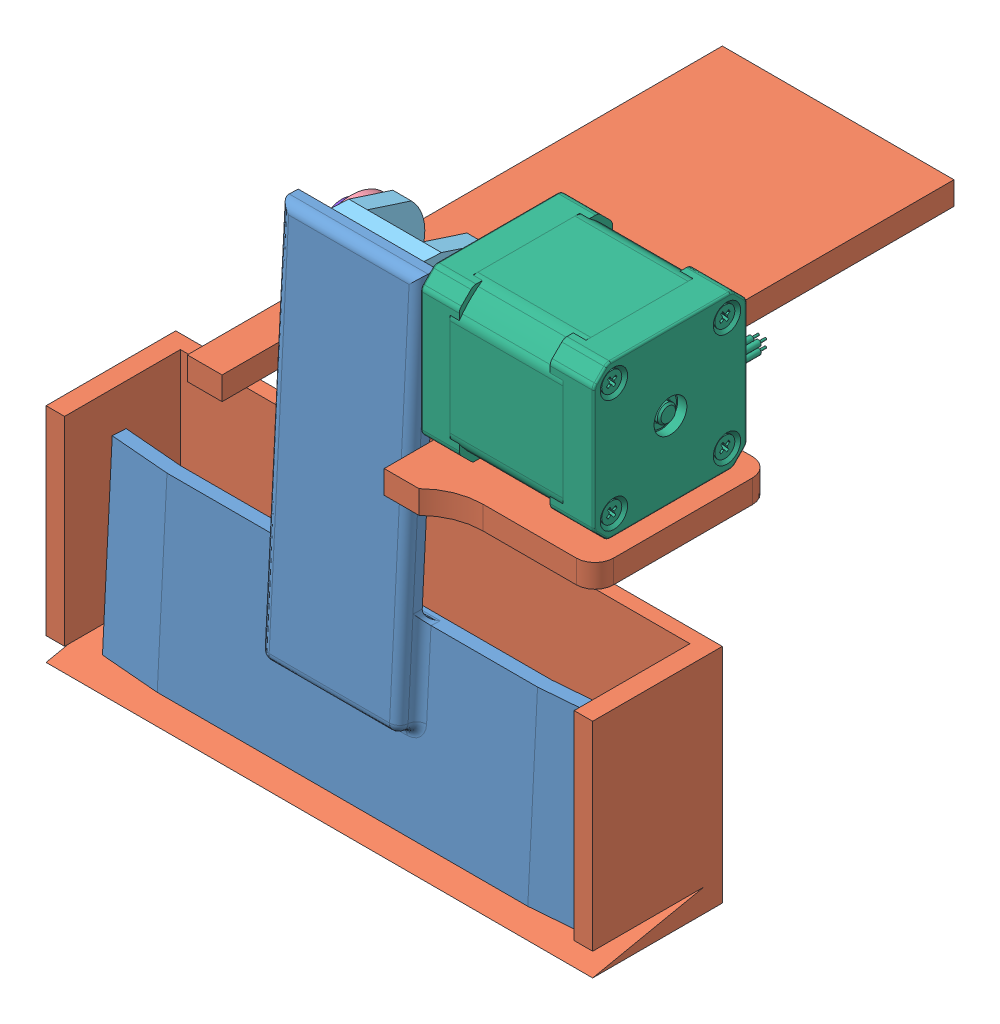
SolidWorks assembly ScoopClawAssembly_m2, configuration Default. Lengths in mm.
Overall size (149.86 138.94 146.69).
8 component instances, 8 part files, 19 mates.
Components (placement in the parent):
- Scooper_m2-1: Scooper_m2 [Default] at (144.6073 -34.5841 76.4289) x (1 0 0) z (0 0.052593 0.998616) size (134.49 132.08 10.33)
- Scooper_Base_m2-1: Scooper_Base_m2 [Default] at (144.6073 -61.534 72.0438) size (149.86 96.84 146.69)
- HC-SR04-UltrasonicSensor v7-2: HC-SR04-UltrasonicSensor v7 [Default] at (144.5683 -48.834 47.0588) x (-1 0 0) z (0 0 1) size (45.45 26.2 17.79)
- Hinge_Part1_base_side-1: Hinge_Part1_base_side [Default] at (144.6073 35.3035 61.4739) size (35.56 29.45 25.4)
- Hinge_Part2__scoop_sdie-1: Hinge_Part2__scoop_sdie [Default] at (144.6073 56.9297 75.4245) x (1 0 0) z (0 0.998616 -0.052593) size (25.4 24.06 25.4)
- 17HM19-2004S-1: 17HM19-2004S [По умолчанию] at (214.4273 69.2601 59.7763) x (0 -0.999984 0.005702) z (0 -0.005702 -0.999984) size (42.19 71.6 51.3)
- Hinge_NEMA17_m2-1: Hinge_NEMA17_m2 [Default] at (162.3873 69.2573 59.755) x (0 -0.999973 0.007334) z (-1 0 0) size (12.7 12.7 38.1)
- Hinge_Cap_m2-1: Hinge_Cap_m2 [Default] at (126.8273 56.195 61.4739) x (0 1 0) z (0 0 1) size (12.7 2.54 12.7)
Mates (geometry in assembly coordinates):
- Concentric1: concentric: cylinder of Scooper_Base_m2-1 through (157.6883 -48.834 58.7088) axis (0 0 -1) radius 8.2697; cylinder of HC-SR04-UltrasonicSensor v7-2 through (157.6883 -48.834 48.6588) axis (0 0 1) radius 8
- Coincident1: coincident: plane of Scooper_Base_m2-1 through (144.6073 -61.534 52.3588) normal (0 0 -1); plane of HC-SR04-UltrasonicSensor v7-2 through (144.5683 -56.2197 52.3588) normal (0 0 1)
- Coincident2: coincident: plane of Scooper_Base_m2-1 through (144.6073 35.3035 72.0438) normal (0 1 0); plane of Hinge_Part1_base_side-1 through (144.6073 35.3035 61.4739) normal (0 -1 0)
- Coincident4: coincident: plane of Scooper_Base_m2-1 through (166.8323 -61.535 74.1739) normal (0 0 1); plane of Hinge_Part1_base_side-1 through (126.8273 48.321 74.1739) normal (0 0 1)
- Distance1: distance = 4.445 mm: plane of Hinge_Part1_base_side-1 through (162.3873 48.321 74.1739) normal (1 0 0); plane of Scooper_Base_m2-1 through (166.8323 -61.535 113.2075) normal (-1 0 0)
- Coincident7: coincident: plane of Hinge_Part1_base_side-1 through (157.3073 52.0471 61.4739) normal (-1 0 0); plane of Hinge_Part2__scoop_sdie-1 through (157.3073 69.2113 67.1471) normal (1 0 0)
- Coincident8: coincident: plane of Scooper_m2-1 through (144.6073 -34.3838 80.2336) normal (0 -0.052593 -0.998616); plane of Hinge_Part2__scoop_sdie-1 through (144.6073 56.9297 75.4245) normal (0 0.052593 0.998616)
- Distance2: distance = 6.35 mm: plane of Scooper_m2-1 through (163.6573 -34.1166 85.3066) normal (1 0 0); plane of Hinge_Part2__scoop_sdie-1 through (157.3073 69.2113 67.1471) normal (1 0 0)
- LimitDistance1: limit distance = 17.4872 mm: point of Scooper_m2-1; plane of Scooper_Base_m2-1 through (144.6073 -61.534 56.1688) normal (0 0 1)
- Distance4: distance = 76.2 mm: line of Scooper_m2-1 through (163.6573 -6.4824 78.7642) axis (-1 0 0); line of Hinge_Part2__scoop_sdie-1 through (131.9073 69.6121 74.7566) axis (1 0 0)
- LimitDistance2: limit distance = 36.8451 mm: plane of Scooper_Base_m2-1 through (144.6073 35.3035 72.0438) normal (0 1 0); line of Scooper_m2-1 through (163.6573 72.1486 74.623) axis (-1 0 0)
- Parallel1: parallel: plane of Scooper_Base_m2-1 through (144.6073 35.3035 72.0438) normal (0 1 0); plane of 17HM19-2004S-1 through (174.9273 35.195 46.8328) normal (0 -1 0)
- Concentric6: concentric: circle of 17HM19-2004S-1; circle of Hinge_NEMA17_m2-1
- Coincident19: coincident: plane of 17HM19-2004S-1 through (164.9273 56.195 61.4739) normal (-1 0 0); plane of Hinge_NEMA17_m2-1 through (164.9273 56.195 61.4739) normal (1 0 0)
- Concentric7: concentric: circle of Hinge_Part1_base_side-1; cylinder of Hinge_NEMA17_m2-1 through (126.8273 56.195 61.4739) axis (1 0 0) radius 5
- Coincident20: coincident: plane of Hinge_Part1_base_side-1 through (162.3873 48.321 74.1739) normal (1 0 0); plane of Hinge_NEMA17_m2-1 through (162.3873 56.195 61.4739) normal (-1 0 0)
- Concentric8: concentric: circle of Hinge_Part2__scoop_sdie-1; cylinder of Hinge_NEMA17_m2-1 through (126.8273 56.195 61.4739) axis (1 0 0) radius 5
- Coincident22: coincident: plane of Hinge_NEMA17_m2-1 through (126.8273 56.195 61.4739) normal (-1 0 0); plane of Hinge_Cap_m2-1 through (126.8273 56.195 61.4739) normal (1 0 0)
- Concentric9: concentric: circle of Hinge_Part1_base_side-1; circle of Hinge_Cap_m2-1
